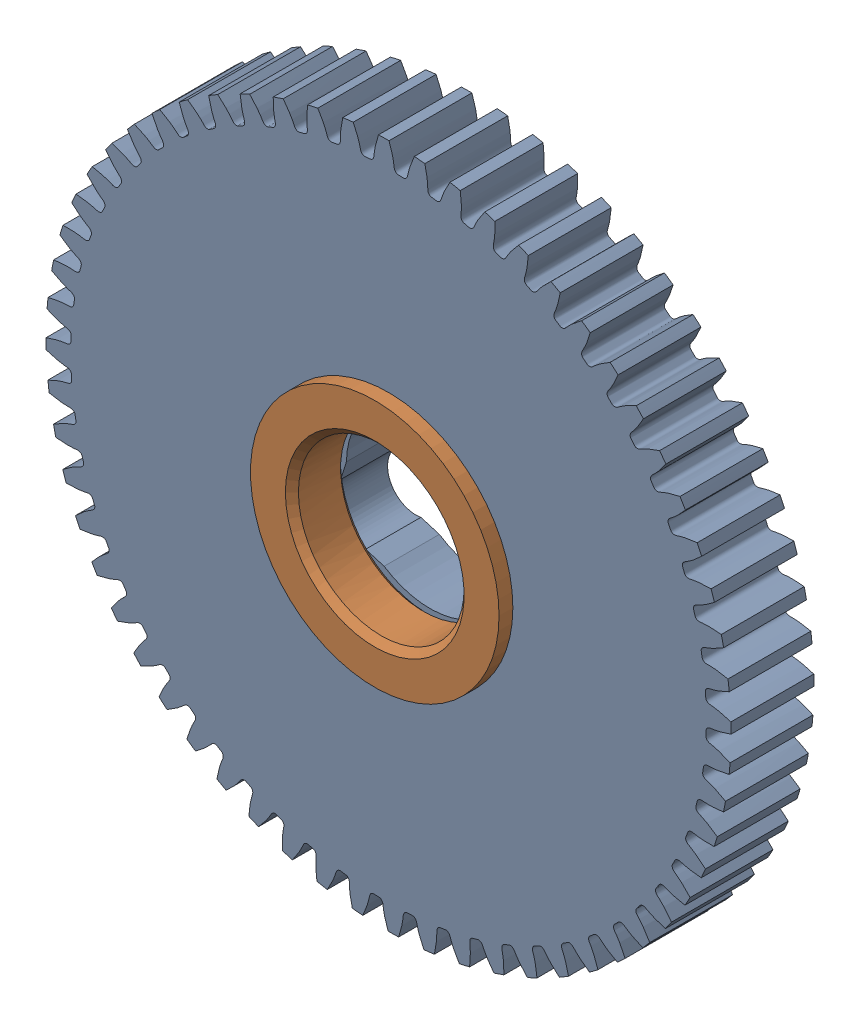
SolidWorks assembly Mirror217-2713-101 Rev1, configuration Default. Lengths in mm.
Overall size (81.88 81.88 12.7).
2 component instances, 2 part files, 0 mates.
Components (placement in the parent):
- Mirror217-2713-001_60t Steel-1: Mirror217-2713-001_60t Steel [Default] at (0 0 -3.302) x (0.999266 -0.038302 0) z (0 0 1) size (78.91 78.91 11.11)
- Mirror217-2428-022 Rev1-1: Mirror217-2428-022 Rev1 [Default] at origin size (28.57 28.57 6.1)
